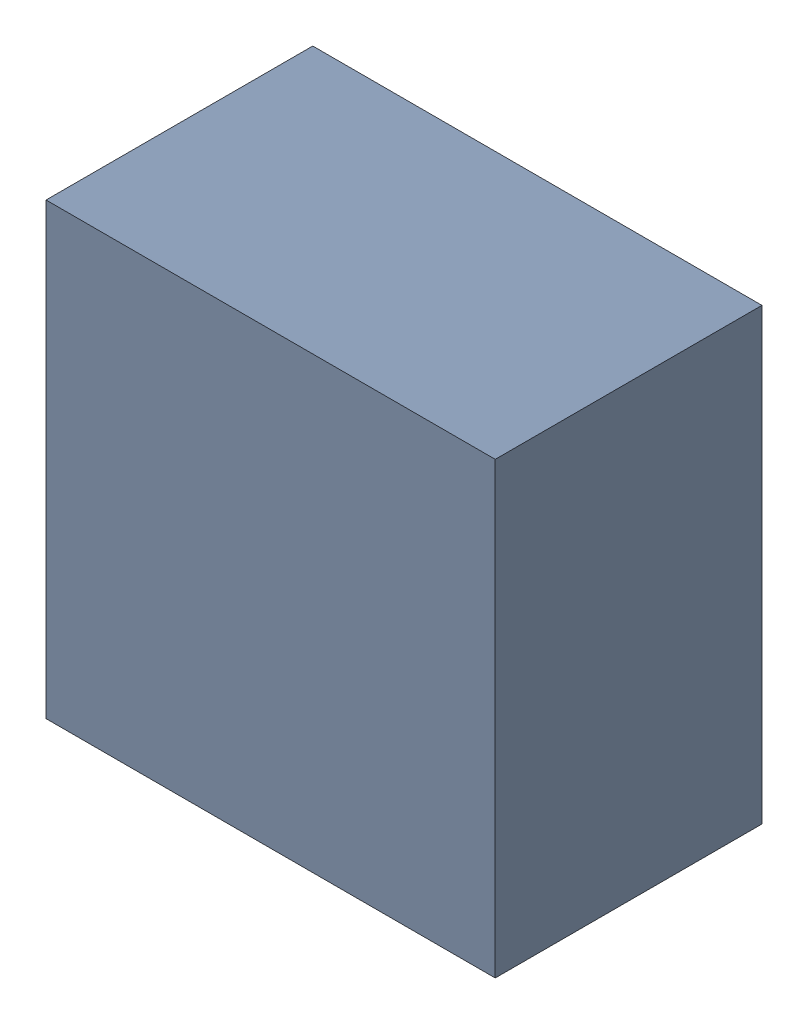
SolidWorks assembly U2, configuration Default. Lengths in mm.
Overall size (12.19 12.19 7.24).
2 component instances, 1 part files, 0 mates.
Components (placement in the parent):
- 580494096-1: 580494096 [Default] at (228.599 101.728 0) size (12.19 12.19 7.24)
  - Extruded_2-1: Extruded_2 [Default] at origin size (12.19 12.19 7.24)
